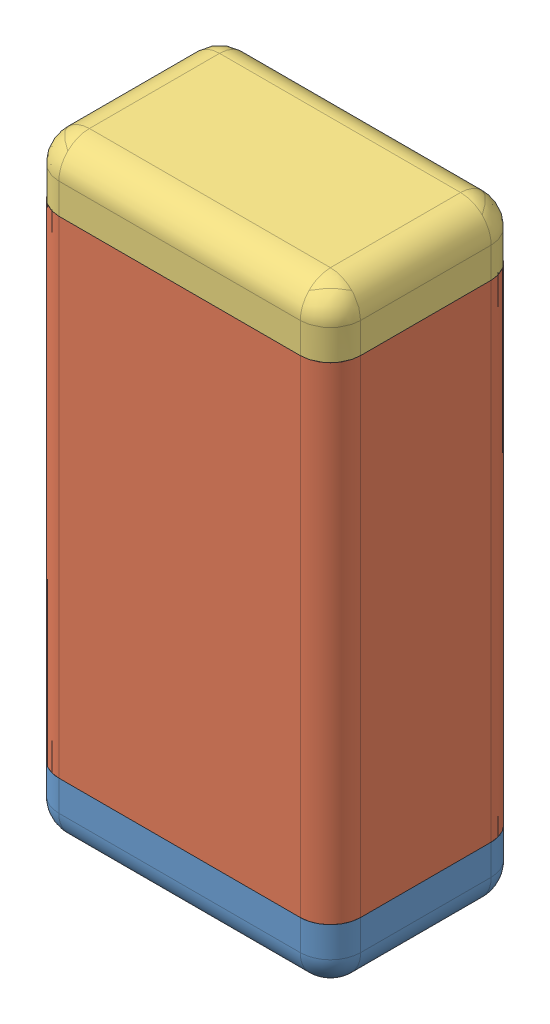
SolidWorks assembly FB1_ASM, configuration Default. Lengths in mm.
Overall size (1.25 2.51 0.79).
4 component instances, 3 part files, 0 mates.
Components (placement in the parent):
- USER_LIBRARY-0805_2012M__RES_ASM-1: USER_LIBRARY-0805_2012M__RES_ASM [Default] at (10.2869 36.4235 -1.7324) x (0 -1 0) z (1 0 0) size (2.51 0.79 1.25)
  - MANIFOLD_SOLID_BREP_51588-1: MANIFOLD_SOLID_BREP_51588 [Default] at origin size (0.25 0.79 1.25)
  - MANIFOLD_SOLID_BREP_52342-1: MANIFOLD_SOLID_BREP_52342 [Default] at origin size (2.01 0.79 1.24)
  - MANIFOLD_SOLID_BREP_57321-1: MANIFOLD_SOLID_BREP_57321 [Default] at origin size (0.25 0.79 1.25)
